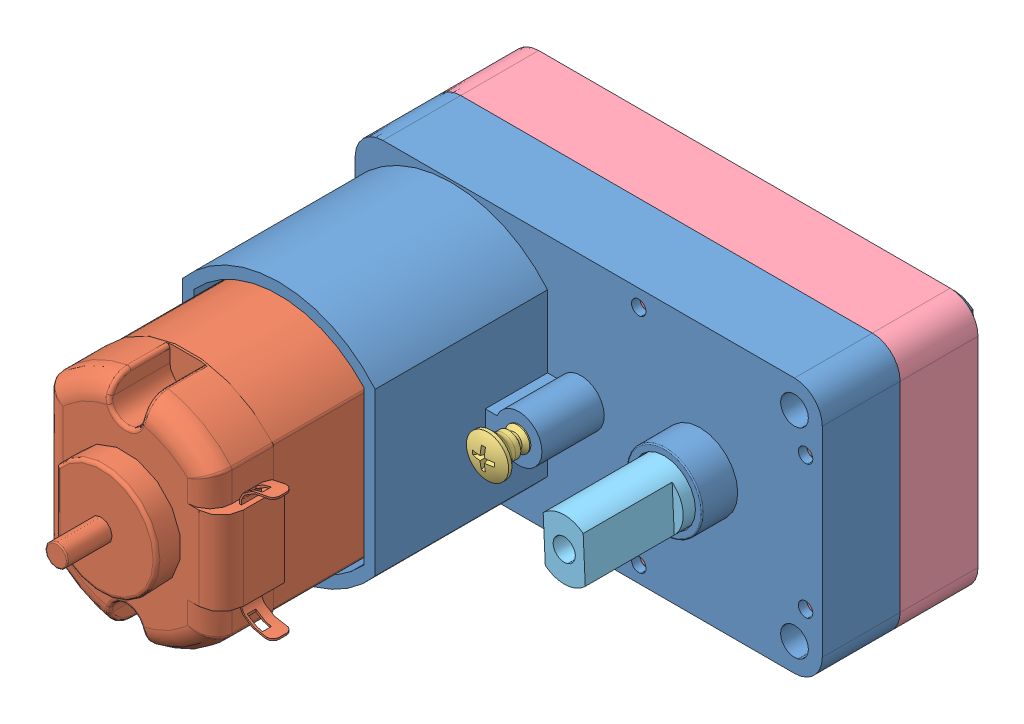
SolidWorks assembly TT_ANGLE_MOTOR, configuration По умолчанию. Lengths in mm.
Overall size (49.04 25.87 58.3).
13 component instances, 11 part files, 0 mates.
Components (placement in the parent):
- 1-1: 1 [По умолчанию] at (18.7579 -8.136 0) size (47.1 23 22.5)
- 2-1: 2 [По умолчанию] at (-11.2666 2.0594 10.6) size (20.08 20 41.9)
- 4-1: 4 [По умолчанию] at (-22.9166 2.0594 5.4) x (0 0 -1) z (1 0 0) size (10.55 3.86 3.98)
- 4-2: 4 [По умолчанию] at (0.3834 2.0594 5.4) x (0 0 -1) z (1 0 0) size (10.55 3.86 3.98)
- 5-1: 5 [По умолчанию] at (18.7579 -8.136 0) x (-1 0 0) z (0 0 -1) size (42 23 15.3)
- 6-1: 6 [По умолчанию] at (11.0834 2.0594 7) x (0.998872 0.047482 0) z (0 0 1) size (5.4 5.4 29.2)
- 7-1: 7 [По умолчанию] at (-0.3166 2.0594 3.6) x (-0.926164 -0.377122 0) z (0 0 -1) size (18.6 18.6 4.5)
- 8-1: 8 [По умолчанию] at (-0.3166 2.0594 -8.2) x (-0.150609 -0.988593 0) z (0 0 1) size (2 2 14.4)
- 9-1: 9 [По умолчанию] at (11.0834 2.0594 1.1) x (-0.822827 -0.568292 0) z (0 0 -1) size (18.6 18.6 4.5)
- 10-1: 10 [По умолчанию] at (-0.3166 2.0594 -1.4) x (-0.973048 -0.230602 0) z (0 0 -1) size (14.65 14.7 4.5)
- 11-1: 11 [По умолчанию] at (11.0834 2.0594 -3.1) x (-0.998872 -0.047482 0) z (0 0 -1) size (14.65 14.7 12.7)
- 12-1: 12 [По умолчанию] at (-8.3166 -6.9406 7) x (0 0 1) z (-1 0 0) size (14.6 4.05 4.15)
- 12-2: 12 [По умолчанию] at (-8.3166 11.0594 7) x (0 0 1) z (-1 0 0) size (14.6 4.05 4.15)
